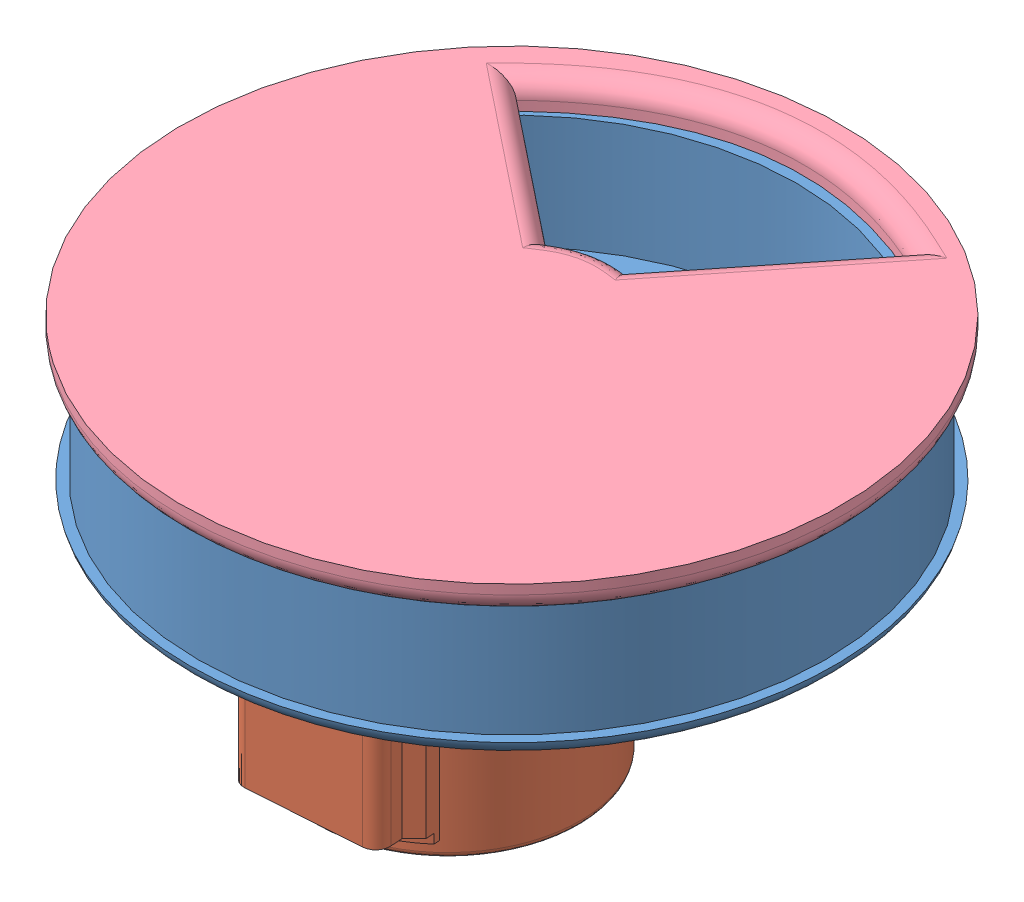
SolidWorks assembly VIBUTHI ASSEMBLY, configuration Default. Lengths in mm.
Overall size (98.46 36.44 98.51).
4 component instances, 4 part files, 7 mates.
Components (placement in the parent):
- CIRCULAR-1: CIRCULAR [Default] at (17.8098 31.3273 59.6769) size (68.5 13.77 68.5)
- 28BYJ-48 - 5 VDC SB-1: 28BYJ-48 - 5 VDC SB [Varsayılan] at (18.3173 10.2073 66.9843) x (0.069297 0 0.997596) z (-0.997596 0 0.069297) size (30.46 29.29 42)
- FAN-2: FAN [Default] at (17.8098 43.3273 59.6769) x (-0.684901 0 0.728636) z (0.728636 0 0.684901) size (59.59 10 59.59)
- Part1-2: Part1 [Default] at (17.8098 43.4273 59.6769) x (0.787152 0 0.616759) z (-0.616759 0 0.787152) size (70 3.96 70.3)
Mates (geometry in assembly coordinates):
- Concentric26: concentric: circle of CIRCULAR-1; circle of Part1-2
- Concentric28: concentric: cylinder of CIRCULAR-1 through (17.8098 31.6573 59.6769) axis (0 -1 0) radius 4.75; cylinder of 28BYJ-48 - 5 VDC SB-1 through (17.8098 39.4773 59.6769) axis (0 1 0) radius 2.46
- Coincident14: coincident: plane of CIRCULAR-1 through (17.8098 29.6573 59.6769) normal (0 -1 0); plane of 28BYJ-48 - 5 VDC SB-1 through (18.3173 29.6573 66.9843) normal (0 1 0)
- Lock1: lock: unknown of CIRCULAR-1; unknown of 28BYJ-48 - 5 VDC SB-1
- Coincident26: coincident: plane of CIRCULAR-1 through (17.8098 43.4273 59.6769) normal (0 1 0); plane of Part1-2 through (17.8098 43.4273 59.6769) normal (0 -1 0)
- Concentric35: concentric: cylinder of 28BYJ-48 - 5 VDC SB-1 through (17.8098 39.4773 59.6769) axis (0 1 0) radius 2.46; cylinder of FAN-2 through (17.8098 39.4773 59.6769) axis (0 -1 0) radius 2.475
- Coincident53: coincident: plane of 28BYJ-48 - 5 VDC SB-1 through (17.8098 33.3273 59.6769) normal (0 1 0); plane of FAN-2 through (17.8098 33.3273 59.6769) normal (0 -1 0)
